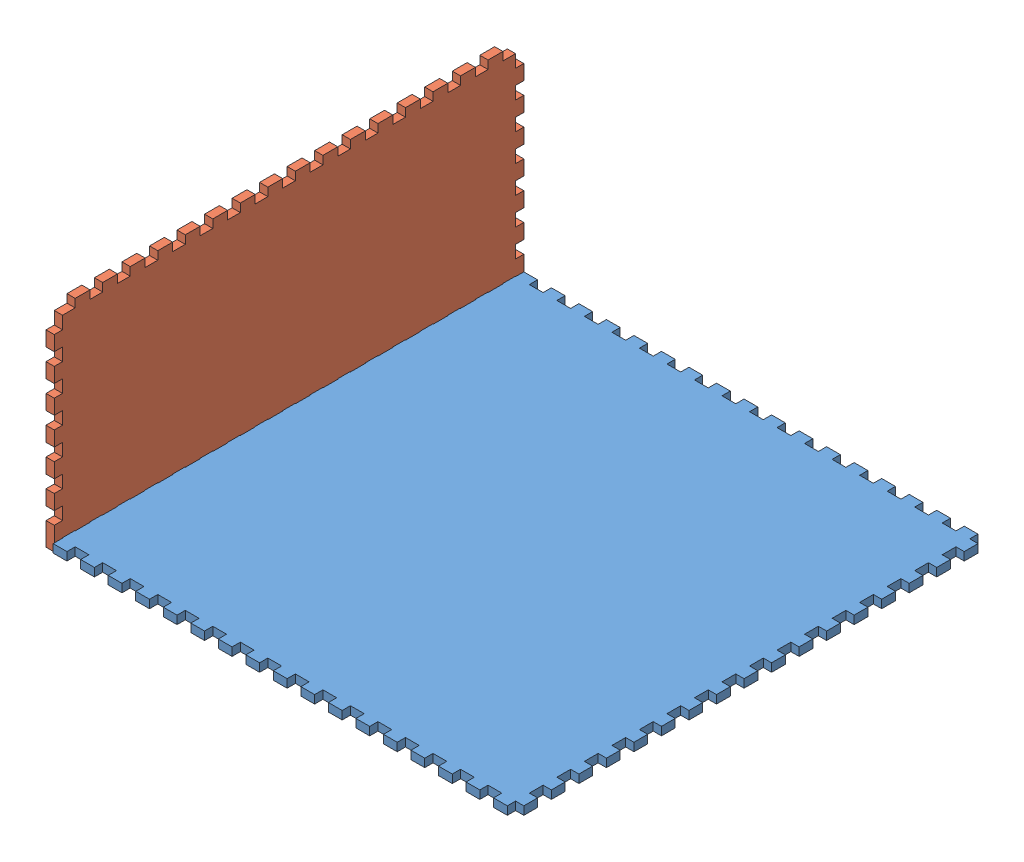
SolidWorks assembly Сборка1, configuration По умолчанию. Lengths in mm.
Overall size (171 76.16 171).
2 component instances, 2 part files, 2 mates.
Components (placement in the parent):
- joint_controlbox_bottom-1: joint_controlbox_bottom [По умолчанию] at origin size (171 3 171)
- joint_controlbox_side-1: joint_controlbox_side [По умолчанию] at (-3 3.1606 -0.4) x (0 0 -1) z (0 -1 0) size (170.6 3 76)
Mates (geometry in assembly coordinates):
- Совпадение1: coincident anti-aligned: plane of joint_controlbox_bottom-1 through (0 3 0) normal (-1 0 0); plane of joint_controlbox_side-1 through (0 3.1606 -0.4) normal (1 0 0)
- Совпадение2: coincident anti-aligned: plane of joint_controlbox_bottom-1 through (0 3 -165) normal (0 0 -1); plane of joint_controlbox_side-1 through (0 0.1606 -165) normal (0 0 1)
